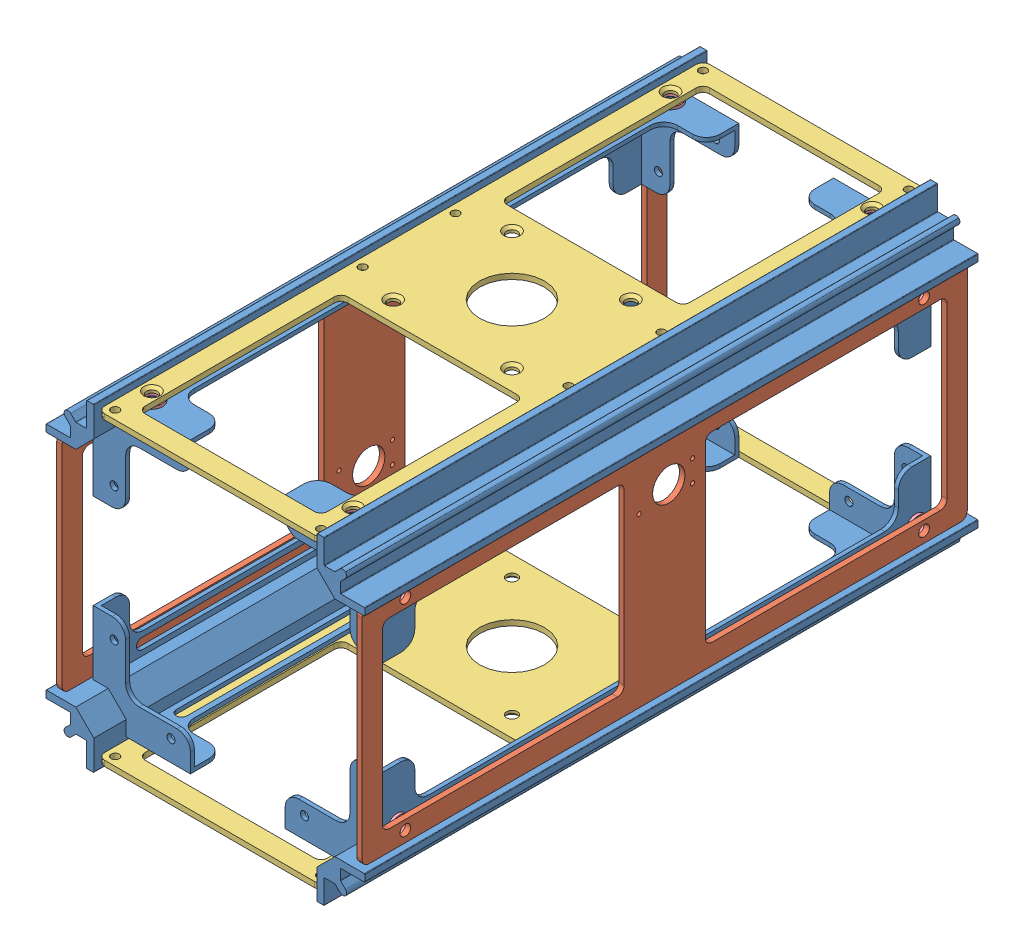
SolidWorks assembly Spirit2U - Frame, configuration Default. Lengths in mm.
Overall size (118 118 227).
24 component instances, 4 part files, 56 mates.
Components (placement in the parent):
- Spirit2U Rail-1: Spirit2U Rail [Default] at (8.2895 -47.6946 -113.5) size (41.46 41.46 227)
- Spirit2U Side panel A-1: Spirit2U Side panel A [Default] at (56.536 -8.1555 39.0404) x (0 0 -1) z (0 -1 0) size (224 2 82.6)
- Spirit2U Side panel A-2: Spirit2U Side panel A [Default] at (-56.536 8.1555 39.0404) x (0 0 -1) z (0 1 0) size (224 2 82.6)
- Spirit2U Rail-2: Spirit2U Rail [Default] at (-47.6946 -8.2895 -113.5) x (0 -1 0) z (0 0 1) size (41.46 41.46 227)
- Spirit2U Rail-3: Spirit2U Rail [Default] at (-8.2895 47.6946 -113.5) x (-1 0 0) z (0 0 1) size (41.46 41.46 227)
- Spirit2U Rail-4: Spirit2U Rail [Default] at (47.6946 8.2895 -113.5) x (0 1 0) z (0 0 1) size (41.46 41.46 227)
- Spirit2U Side panel B-1: Spirit2U Side panel B [Default] at (-8.1555 -54.536 -39.0404) x (0 0 1) z (-1 0 0) size (224 2 82.6)
- Spirit2U Side panel B-2: Spirit2U Side panel B [Default] at (-8.1555 54.536 39.0404) x (0 0 -1) z (-1 0 0) size (224 2 82.6)
- 93650A110_MOISTURE-RESISTANT CUSHIONING WASHER-1: 93650A110_MOISTURE-RESISTANT CUSHIONING WASHER [93650A110] at (-53.536 -37.3 -96) x (0 0 -1) z (1 0 0) size (7.92 7.92 1)
- 93650A110_MOISTURE-RESISTANT CUSHIONING WASHER-2: 93650A110_MOISTURE-RESISTANT CUSHIONING WASHER [93650A110] at (-53.536 37.3 -96) x (0 0 -1) z (1 0 0) size (7.92 7.92 1)
- 93650A110_MOISTURE-RESISTANT CUSHIONING WASHER-3: 93650A110_MOISTURE-RESISTANT CUSHIONING WASHER [93650A110] at (-53.536 37.3 96) x (0 0 -1) z (1 0 0) size (7.92 7.92 1)
- 93650A110_MOISTURE-RESISTANT CUSHIONING WASHER-4: 93650A110_MOISTURE-RESISTANT CUSHIONING WASHER [93650A110] at (-53.536 -37.3 96) x (0 0 -1) z (1 0 0) size (7.92 7.92 1)
- 93650A110_MOISTURE-RESISTANT CUSHIONING WASHER-5: 93650A110_MOISTURE-RESISTANT CUSHIONING WASHER [93650A110] at (-37.3 -53.536 96) x (1 0 0) z (0 1 0) size (7.92 7.92 1)
- 93650A110_MOISTURE-RESISTANT CUSHIONING WASHER-6: 93650A110_MOISTURE-RESISTANT CUSHIONING WASHER [93650A110] at (37.3 -53.536 96) x (1 0 0) z (0 1 0) size (7.92 7.92 1)
- 93650A110_MOISTURE-RESISTANT CUSHIONING WASHER-7: 93650A110_MOISTURE-RESISTANT CUSHIONING WASHER [93650A110] at (-37.3 -53.536 -96) x (1 0 0) z (0 1 0) size (7.92 7.92 1)
- 93650A110_MOISTURE-RESISTANT CUSHIONING WASHER-8: 93650A110_MOISTURE-RESISTANT CUSHIONING WASHER [93650A110] at (37.3 -53.536 -96) x (1 0 0) z (0 1 0) size (7.92 7.92 1)
- 93650A110_MOISTURE-RESISTANT CUSHIONING WASHER-9: 93650A110_MOISTURE-RESISTANT CUSHIONING WASHER [93650A110] at (53.536 -37.3 -96) x (0 0 1) z (-1 0 0) size (7.92 7.92 1)
- 93650A110_MOISTURE-RESISTANT CUSHIONING WASHER-10: 93650A110_MOISTURE-RESISTANT CUSHIONING WASHER [93650A110] at (53.536 37.3 96) x (0 0 1) z (-1 0 0) size (7.92 7.92 1)
- 93650A110_MOISTURE-RESISTANT CUSHIONING WASHER-11: 93650A110_MOISTURE-RESISTANT CUSHIONING WASHER [93650A110] at (54.536 -37.3 96) x (0 0.807296 0.590146) z (1 0 0) size (7.92 7.92 1)
- 93650A110_MOISTURE-RESISTANT CUSHIONING WASHER-12: 93650A110_MOISTURE-RESISTANT CUSHIONING WASHER [93650A110] at (53.536 37.3 -96) x (0 0 1) z (-1 0 0) size (7.92 7.92 1)
- 93650A110_MOISTURE-RESISTANT CUSHIONING WASHER-13: 93650A110_MOISTURE-RESISTANT CUSHIONING WASHER [93650A110] at (-37.3 53.536 96) x (1 0 0) z (0 -1 0) size (7.92 7.92 1)
- 93650A110_MOISTURE-RESISTANT CUSHIONING WASHER-14: 93650A110_MOISTURE-RESISTANT CUSHIONING WASHER [93650A110] at (37.3 53.536 -96) x (1 0 0) z (0 -1 0) size (7.92 7.92 1)
- 93650A110_MOISTURE-RESISTANT CUSHIONING WASHER-15: 93650A110_MOISTURE-RESISTANT CUSHIONING WASHER [93650A110] at (37.3 53.536 96) x (1 0 0) z (0 -1 0) size (7.92 7.92 1)
- 93650A110_MOISTURE-RESISTANT CUSHIONING WASHER-16: 93650A110_MOISTURE-RESISTANT CUSHIONING WASHER [93650A110] at (-37.3 53.536 -96) x (1 0 0) z (0 -1 0) size (7.92 7.92 1)
Mates (geometry in assembly coordinates):
- Coincident1: coincident: plane of Spirit2U Rail-1 through (8.2895 -47.6946 -113.5) normal (0 0 -1); plane of Spirit2U Rail-4 through (47.6946 8.2895 -113.5) normal (0 0 -1)
- Coincident2: coincident: plane of Spirit2U Rail-1 through (8.2895 -47.6946 -113.5) normal (0 0 -1); plane of Spirit2U Rail-2 through (-47.6946 -8.2895 -113.5) normal (0 0 -1)
- Coincident3: coincident: plane of Spirit2U Rail-1 through (8.2895 -47.6946 -113.5) normal (0 0 -1); plane of Spirit2U Rail-3 through (-8.2895 47.6946 -113.5) normal (0 0 -1)
- Distance1: distance = 113.5 mm: plane of Spirit2U Rail-1 through (8.2895 -47.6946 -113.5) normal (0 0 -1); plane of assembly through (0 0 0) normal (0 0 1)
- Distance2: distance = 59 mm: plane of Spirit2U Rail-1 through (59 45 113.5) normal (1 0 0); plane of assembly through (0 0 0) normal (1 0 0)
- Coincident6: coincident: plane of Spirit2U Rail-1 through (59 45 113.5) normal (1 0 0); plane of Spirit2U Rail-2 through (59 -45 113.5) normal (1 0 0)
- Symmetric2: symmetric: plane of Spirit2U Rail-1 through (59 45 113.5) normal (1 0 0); plane of Spirit2U Rail-4 through (-59 45 113.5) normal (-1 0 0); plane of assembly
- Coincident7: coincident: plane of Spirit2U Rail-3 through (-59 -45 113.5) normal (-1 0 0); plane of Spirit2U Rail-4 through (-59 45 113.5) normal (-1 0 0)
- Distance3: distance = 59 mm: plane of assembly through (0 0 0) normal (0 1 0); plane of Spirit2U Rail-1 through (45 59 113.5) normal (0 1 0)
- Coincident9: coincident: plane of Spirit2U Rail-1 through (45 59 113.5) normal (0 1 0); plane of Spirit2U Rail-4 through (-45 59 113.5) normal (0 1 0)
- Coincident10: coincident: plane of Spirit2U Rail-2 through (45 -59 113.5) normal (0 -1 0); plane of Spirit2U Rail-3 through (-45 -59 113.5) normal (0 -1 0)
- Symmetric4: symmetric: plane of Spirit2U Rail-1 through (45 59 113.5) normal (0 1 0); plane of Spirit2U Rail-2 through (45 -59 113.5) normal (0 -1 0); plane of assembly
- Concentric120: concentric: cylinder of Spirit2U Rail-1 through (43.536 37.3 -96) axis (1 0 0) radius 2; cylinder of Spirit2U Side panel A-1 through (54.536 37.3 -96) axis (1 0 0) radius 2
- Parallel3: parallel: plane of Spirit2U Rail-1 through (8.2895 -47.6946 -101.5) normal (0 0 -1); plane of Spirit2U Side panel A-1 through (56.536 -8.1555 -112) normal (0 0 -1)
- Concentric121: concentric: cylinder of Spirit2U Rail-1 through (37.3 43.536 -96) axis (0 1 0) radius 2; cylinder of Spirit2U Side panel B-2 through (37.3 56.536 -96) axis (0 -1 0) radius 2
- Parallel4: parallel: plane of Spirit2U Rail-1 through (8.2895 -47.6946 -101.5) normal (0 0 -1); plane of Spirit2U Side panel B-2 through (-8.1555 54.536 -112) normal (0 0 -1)
- Concentric122: concentric: cylinder of Spirit2U Rail-2 through (37.3 -43.536 -96) axis (0 -1 0) radius 2; cylinder of Spirit2U Side panel B-1 through (37.3 -56.536 -96) axis (0 1 0) radius 2
- Parallel5: parallel: plane of Spirit2U Rail-2 through (-47.6946 -8.2895 -101.5) normal (0 0 -1); plane of Spirit2U Side panel B-1 through (-8.1555 -54.536 -112) normal (0 0 -1)
- Concentric123: concentric: cylinder of Spirit2U Side panel A-2 through (-72.9226 -37.3 -96) axis (-1 0 0) radius 2; cylinder of Spirit2U Rail-3 through (-43.536 -37.3 -96) axis (-1 0 0) radius 2
- Parallel6: parallel: plane of Spirit2U Side panel A-2 through (-74.9226 8.1555 -112) normal (0 0 -1); plane of Spirit2U Rail-3 through (-8.2895 47.6946 -101.5) normal (0 0 -1)
- Concentric124: concentric: cylinder of Spirit2U Rail-2 through (43.536 -37.3 96) axis (1 0 0) radius 2; cylinder of 93650A110_MOISTURE-RESISTANT CUSHIONING WASHER-11 through (53.536 -37.3 96) axis (1 0 0) radius 2.1844
- Coincident11: coincident: plane of Spirit2U Rail-2 through (53.536 -33.3 113.5) normal (1 0 0); plane of 93650A110_MOISTURE-RESISTANT CUSHIONING WASHER-11 through (53.536 -37.3 96) normal (-1 0 0)
- Coincident12: coincident: plane of Spirit2U Rail-1 through (53.536 41.3 113.5) normal (1 0 0); plane of 93650A110_MOISTURE-RESISTANT CUSHIONING WASHER-10 through (53.536 37.3 96) normal (-1 0 0)
- Coincident13: coincident: plane of Spirit2U Rail-2 through (53.536 -33.3 113.5) normal (1 0 0); plane of 93650A110_MOISTURE-RESISTANT CUSHIONING WASHER-9 through (53.536 -37.3 -96) normal (-1 0 0)
- Coincident14: coincident: plane of Spirit2U Rail-1 through (53.536 41.3 113.5) normal (1 0 0); plane of 93650A110_MOISTURE-RESISTANT CUSHIONING WASHER-12 through (53.536 37.3 -96) normal (-1 0 0)
- Concentric125: concentric: cylinder of Spirit2U Rail-2 through (43.536 -37.3 -96) axis (1 0 0) radius 2; cylinder of 93650A110_MOISTURE-RESISTANT CUSHIONING WASHER-9 through (54.536 -37.3 -96) axis (-1 0 0) radius 2.1844
- Concentric126: concentric: cylinder of Spirit2U Rail-1 through (43.536 37.3 -96) axis (1 0 0) radius 2; cylinder of 93650A110_MOISTURE-RESISTANT CUSHIONING WASHER-12 through (54.536 37.3 -96) axis (-1 0 0) radius 2.1844
- Concentric127: concentric: cylinder of Spirit2U Rail-1 through (43.536 37.3 96) axis (1 0 0) radius 2; cylinder of 93650A110_MOISTURE-RESISTANT CUSHIONING WASHER-10 through (54.536 37.3 96) axis (-1 0 0) radius 2.1844
- Coincident15: coincident: plane of Spirit2U Side panel A-1 through (54.536 -8.1555 39.0404) normal (-1 0 0); plane of 93650A110_MOISTURE-RESISTANT CUSHIONING WASHER-10 through (54.536 37.3 96) normal (1 0 0)
- Coincident16: coincident: plane of Spirit2U Rail-2 through (41.3 -53.536 113.5) normal (0 -1 0); plane of 93650A110_MOISTURE-RESISTANT CUSHIONING WASHER-6 through (37.3 -53.536 96) normal (0 1 0)
- Coincident17: coincident: plane of Spirit2U Rail-3 through (-33.3 -53.536 113.5) normal (0 -1 0); plane of 93650A110_MOISTURE-RESISTANT CUSHIONING WASHER-5 through (-37.3 -53.536 96) normal (0 1 0)
- Coincident18: coincident: plane of Spirit2U Rail-3 through (-33.3 -53.536 113.5) normal (0 -1 0); plane of 93650A110_MOISTURE-RESISTANT CUSHIONING WASHER-7 through (-37.3 -53.536 -96) normal (0 1 0)
- Coincident19: coincident: plane of Spirit2U Rail-2 through (41.3 -53.536 113.5) normal (0 -1 0); plane of 93650A110_MOISTURE-RESISTANT CUSHIONING WASHER-8 through (37.3 -53.536 -96) normal (0 1 0)
- Concentric128: concentric: cylinder of Spirit2U Rail-2 through (37.3 -43.536 -96) axis (0 -1 0) radius 2; cylinder of 93650A110_MOISTURE-RESISTANT CUSHIONING WASHER-8 through (37.3 -54.536 -96) axis (0 1 0) radius 2.1844
- Concentric129: concentric: cylinder of Spirit2U Rail-3 through (-37.3 -43.536 -96) axis (0 -1 0) radius 2; cylinder of 93650A110_MOISTURE-RESISTANT CUSHIONING WASHER-7 through (-37.3 -54.536 -96) axis (0 1 0) radius 2.1844
- Concentric130: concentric: cylinder of Spirit2U Rail-3 through (-37.3 -43.536 96) axis (0 -1 0) radius 2; cylinder of 93650A110_MOISTURE-RESISTANT CUSHIONING WASHER-5 through (-37.3 -54.536 96) axis (0 1 0) radius 2.1844
- Concentric131: concentric: cylinder of Spirit2U Rail-2 through (37.3 -43.536 96) axis (0 -1 0) radius 2; cylinder of 93650A110_MOISTURE-RESISTANT CUSHIONING WASHER-6 through (37.3 -54.536 96) axis (0 1 0) radius 2.1844
- Coincident20: coincident: plane of Spirit2U Side panel B-1 through (-8.1555 -54.536 -39.0404) normal (0 1 0); plane of 93650A110_MOISTURE-RESISTANT CUSHIONING WASHER-6 through (37.3 -54.536 96) normal (0 -1 0)
- Coincident21: coincident: plane of Spirit2U Rail-4 through (-41.3 53.536 113.5) normal (0 1 0); plane of 93650A110_MOISTURE-RESISTANT CUSHIONING WASHER-16 through (-37.3 53.536 -96) normal (0 -1 0)
- Coincident22: coincident: plane of Spirit2U Rail-4 through (-41.3 53.536 113.5) normal (0 1 0); plane of 93650A110_MOISTURE-RESISTANT CUSHIONING WASHER-13 through (-37.3 53.536 96) normal (0 -1 0)
- Coincident23: coincident: plane of Spirit2U Rail-1 through (33.3 53.536 113.5) normal (0 1 0); plane of 93650A110_MOISTURE-RESISTANT CUSHIONING WASHER-14 through (37.3 53.536 -96) normal (0 -1 0)
- Coincident24: coincident: plane of Spirit2U Rail-1 through (33.3 53.536 113.5) normal (0 1 0); plane of 93650A110_MOISTURE-RESISTANT CUSHIONING WASHER-15 through (37.3 53.536 96) normal (0 -1 0)
- Concentric132: concentric: cylinder of Spirit2U Rail-4 through (-37.3 43.536 96) axis (0 1 0) radius 2; cylinder of 93650A110_MOISTURE-RESISTANT CUSHIONING WASHER-13 through (-37.3 54.536 96) axis (0 -1 0) radius 2.1844
- Concentric133: concentric: cylinder of Spirit2U Rail-1 through (37.3 43.536 96) axis (0 1 0) radius 2; cylinder of 93650A110_MOISTURE-RESISTANT CUSHIONING WASHER-15 through (37.3 54.536 96) axis (0 -1 0) radius 2.1844
- Concentric134: concentric: cylinder of Spirit2U Rail-1 through (37.3 43.536 -96) axis (0 1 0) radius 2; cylinder of 93650A110_MOISTURE-RESISTANT CUSHIONING WASHER-14 through (37.3 54.536 -96) axis (0 -1 0) radius 2.1844
- Concentric135: concentric: cylinder of Spirit2U Rail-4 through (-37.3 43.536 -96) axis (0 1 0) radius 2; cylinder of 93650A110_MOISTURE-RESISTANT CUSHIONING WASHER-16 through (-37.3 54.536 -96) axis (0 -1 0) radius 2.1844
- Coincident25: coincident: plane of Spirit2U Side panel B-2 through (-8.1555 54.536 39.0404) normal (0 -1 0); plane of 93650A110_MOISTURE-RESISTANT CUSHIONING WASHER-16 through (-37.3 54.536 -96) normal (0 1 0)
- Coincident26: coincident: plane of Spirit2U Rail-4 through (-53.536 33.3 113.5) normal (-1 0 0); plane of 93650A110_MOISTURE-RESISTANT CUSHIONING WASHER-2 through (-53.536 37.3 -96) normal (1 0 0)
- Coincident27: coincident: plane of Spirit2U Rail-4 through (-53.536 33.3 113.5) normal (-1 0 0); plane of 93650A110_MOISTURE-RESISTANT CUSHIONING WASHER-3 through (-53.536 37.3 96) normal (1 0 0)
- Coincident28: coincident: plane of Spirit2U Rail-3 through (-53.536 -41.3 113.5) normal (-1 0 0); plane of 93650A110_MOISTURE-RESISTANT CUSHIONING WASHER-1 through (-53.536 -37.3 -96) normal (1 0 0)
- Coincident29: coincident: plane of Spirit2U Rail-3 through (-53.536 -41.3 113.5) normal (-1 0 0); plane of 93650A110_MOISTURE-RESISTANT CUSHIONING WASHER-4 through (-53.536 -37.3 96) normal (1 0 0)
- Concentric136: concentric: cylinder of Spirit2U Rail-3 through (-43.536 -37.3 96) axis (-1 0 0) radius 2; cylinder of 93650A110_MOISTURE-RESISTANT CUSHIONING WASHER-4 through (-54.536 -37.3 96) axis (1 0 0) radius 2.1844
- Concentric137: concentric: cylinder of Spirit2U Rail-4 through (-43.536 37.3 96) axis (-1 0 0) radius 2; cylinder of 93650A110_MOISTURE-RESISTANT CUSHIONING WASHER-3 through (-54.536 37.3 96) axis (1 0 0) radius 2.1844
- Concentric138: concentric: cylinder of Spirit2U Rail-3 through (-43.536 -37.3 -96) axis (-1 0 0) radius 2; cylinder of 93650A110_MOISTURE-RESISTANT CUSHIONING WASHER-1 through (-54.536 -37.3 -96) axis (1 0 0) radius 2.1844
- Concentric139: concentric: cylinder of Spirit2U Rail-4 through (-43.536 37.3 -96) axis (-1 0 0) radius 2; cylinder of 93650A110_MOISTURE-RESISTANT CUSHIONING WASHER-2 through (-54.536 37.3 -96) axis (1 0 0) radius 2.1844
- Coincident30: coincident: plane of Spirit2U Side panel A-2 through (-54.536 8.1555 39.0404) normal (1 0 0); plane of 93650A110_MOISTURE-RESISTANT CUSHIONING WASHER-2 through (-54.536 37.3 -96) normal (-1 0 0)
